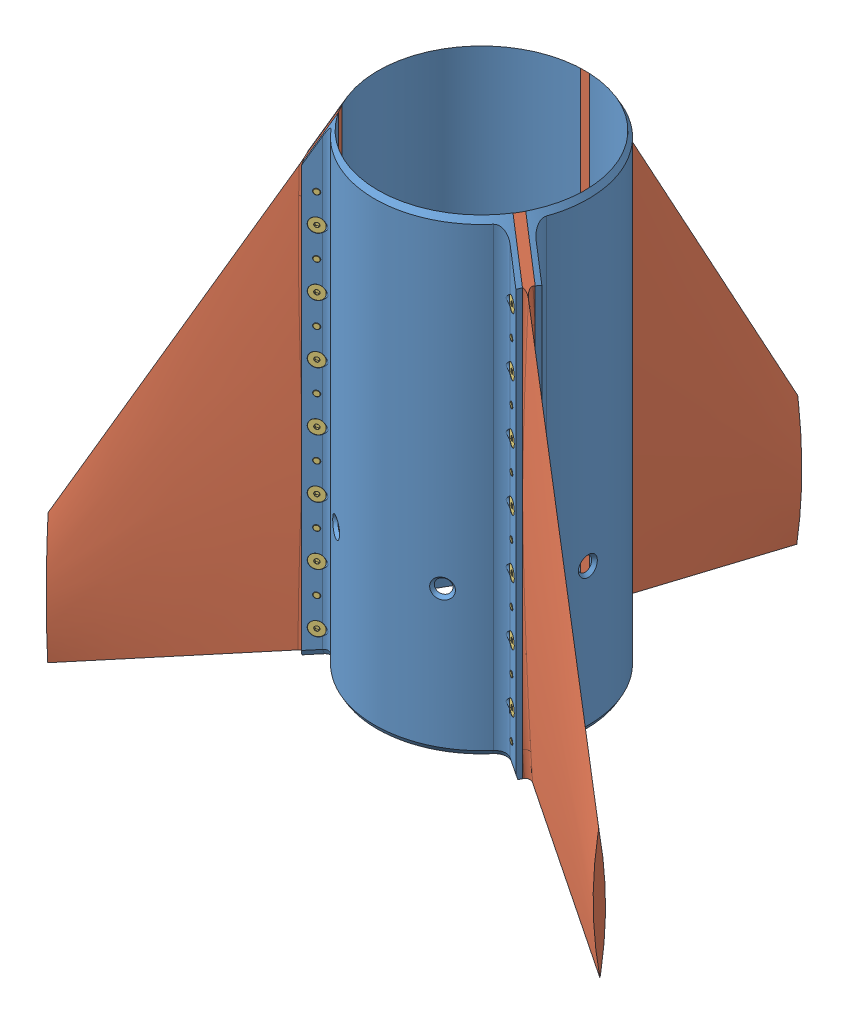
SolidWorks assembly Fin Can 3 Fin Asm 25-20, configuration Default. Lengths in mm.
Overall size (544.77 508.03 473.71).
48 component instances, 3 part files, 14 mates.
Components (placement in the parent):
- Binder Fin Can Section 3 25-20-1: Binder Fin Can Section 3 25-20 [Default] at origin size (110.04 463.46 186.39)
- BiconvexFin 3 Fin Fillet 25-20-4: BiconvexFin 3 Fin Fillet 25-20 [Default] at (85.524 466.7433 54.8623) x (0 -1 0) z (0.866025 0 0.5) size (507.85 12.04 209.48)
- BiconvexFin 3 Fin Fillet 25-20-5: BiconvexFin 3 Fin Fillet 25-20 [Default] at (4.7501 466.7433 -101.4971) x (0 -1 0) z (0 0 -1) size (507.85 12.04 209.48)
- BiconvexFin 3 Fin Fillet 25-20-6: BiconvexFin 3 Fin Fillet 25-20 [Default] at (-90.2741 466.7433 46.6348) x (0 -1 0) z (-0.866025 0 0.5) size (507.85 12.04 209.48)
- Binder Fin Can Section 3 25-20-2: Binder Fin Can Section 3 25-20 [Default] at (-0.0006 0.0001 0) x (-0.5 0 -0.866025) z (0.866025 0 -0.5) size (110.04 463.46 186.39)
- Binder Fin Can Section 3 25-20-3: Binder Fin Can Section 3 25-20 [Default] at (0 -0.0001 0) x (-0.5 0 0.866025) z (-0.866025 0 -0.5) size (110.04 463.46 186.39)
- 91253A307_Black-Oxide Alloy Steel Hex Drive Flat Head Screw-1: 91253A307_Black-Oxide Alloy Steel Hex Drive Flat Head Screw [91253A307] at (0.3215 28.575 -115.7846) x (0 -0.777599 0.628761) z (-1 0 0) size (13.49 13.49 19.62)
- 91253A307_Black-Oxide Alloy Steel Hex Drive Flat Head Screw-2: 91253A307_Black-Oxide Alloy Steel Hex Drive Flat Head Screw [91253A307] at (0.3215 85.725 -115.7846) x (0 -0.777599 0.628761) z (-1 0 0) size (13.49 13.49 19.62)
- 91253A307_Black-Oxide Alloy Steel Hex Drive Flat Head Screw-3: 91253A307_Black-Oxide Alloy Steel Hex Drive Flat Head Screw [91253A307] at (0.3215 142.875 -115.7846) x (0 -0.777599 0.628761) z (-1 0 0) size (13.49 13.49 19.62)
- 91253A307_Black-Oxide Alloy Steel Hex Drive Flat Head Screw-4: 91253A307_Black-Oxide Alloy Steel Hex Drive Flat Head Screw [91253A307] at (0.3215 200.025 -115.7846) x (0 -0.777599 0.628761) z (-1 0 0) size (13.49 13.49 19.62)
- 91253A307_Black-Oxide Alloy Steel Hex Drive Flat Head Screw-28: 91253A307_Black-Oxide Alloy Steel Hex Drive Flat Head Screw [91253A307] at (-0.3221 57.15 -115.7846) x (0 0.917872 0.396876) z (1 0 0) size (13.49 13.49 19.62)
- 91253A307_Black-Oxide Alloy Steel Hex Drive Flat Head Screw-29: 91253A307_Black-Oxide Alloy Steel Hex Drive Flat Head Screw [91253A307] at (-0.3221 114.3 -115.7846) x (0 0.917872 0.396876) z (1 0 0) size (13.49 13.49 19.62)
- 91253A307_Black-Oxide Alloy Steel Hex Drive Flat Head Screw-30: 91253A307_Black-Oxide Alloy Steel Hex Drive Flat Head Screw [91253A307] at (-0.3221 171.45 -115.7846) x (0 0.917872 0.396876) z (1 0 0) size (13.49 13.49 19.62)
- 91253A307_Black-Oxide Alloy Steel Hex Drive Flat Head Screw-31: 91253A307_Black-Oxide Alloy Steel Hex Drive Flat Head Screw [91253A307] at (-0.3221 228.6 -115.7846) x (0 0.917872 0.396876) z (1 0 0) size (13.49 13.49 19.62)
- 91253A307_Black-Oxide Alloy Steel Hex Drive Flat Head Screw-35: 91253A307_Black-Oxide Alloy Steel Hex Drive Flat Head Screw [91253A307] at (100.1114 28.5749 58.1712) x (-0.866025 0 -0.5) z (0.5 0 -0.866025) size (13.49 13.49 19.62)
- 91253A307_Black-Oxide Alloy Steel Hex Drive Flat Head Screw-36: 91253A307_Black-Oxide Alloy Steel Hex Drive Flat Head Screw [91253A307] at (100.1114 85.7249 58.1712) x (-0.866025 0 -0.5) z (0.5 0 -0.866025) size (13.49 13.49 19.62)
- 91253A307_Black-Oxide Alloy Steel Hex Drive Flat Head Screw-37: 91253A307_Black-Oxide Alloy Steel Hex Drive Flat Head Screw [91253A307] at (100.1114 142.8749 58.1712) x (-0.866025 0 -0.5) z (0.5 0 -0.866025) size (13.49 13.49 19.62)
- 91253A307_Black-Oxide Alloy Steel Hex Drive Flat Head Screw-38: 91253A307_Black-Oxide Alloy Steel Hex Drive Flat Head Screw [91253A307] at (100.1114 200.0249 58.1712) x (-0.866025 0 -0.5) z (0.5 0 -0.866025) size (13.49 13.49 19.62)
- 91253A307_Black-Oxide Alloy Steel Hex Drive Flat Head Screw-42: 91253A307_Black-Oxide Alloy Steel Hex Drive Flat Head Screw [91253A307] at (100.4334 57.1499 57.6134) x (0.414746 0.877865 0.239454) z (-0.5 0 0.866025) size (13.49 13.49 19.62)
- 91253A307_Black-Oxide Alloy Steel Hex Drive Flat Head Screw-43: 91253A307_Black-Oxide Alloy Steel Hex Drive Flat Head Screw [91253A307] at (100.4334 114.2999 57.6134) x (0.414746 0.877865 0.239454) z (-0.5 0 0.866025) size (13.49 13.49 19.62)
- 91253A307_Black-Oxide Alloy Steel Hex Drive Flat Head Screw-44: 91253A307_Black-Oxide Alloy Steel Hex Drive Flat Head Screw [91253A307] at (100.4334 171.4499 57.6134) x (0.414746 0.877865 0.239454) z (-0.5 0 0.866025) size (13.49 13.49 19.62)
- 91253A307_Black-Oxide Alloy Steel Hex Drive Flat Head Screw-45: 91253A307_Black-Oxide Alloy Steel Hex Drive Flat Head Screw [91253A307] at (100.4334 228.5999 57.6134) x (0.414746 0.877865 0.239454) z (-0.5 0 0.866025) size (13.49 13.49 19.62)
- 91253A307_Black-Oxide Alloy Steel Hex Drive Flat Head Screw-49: 91253A307_Black-Oxide Alloy Steel Hex Drive Flat Head Screw [91253A307] at (-100.4339 28.5751 57.6136) x (-0.801823 -0.377852 0.462933) z (0.5 0 0.866025) size (13.49 13.49 19.62)
- 91253A307_Black-Oxide Alloy Steel Hex Drive Flat Head Screw-50: 91253A307_Black-Oxide Alloy Steel Hex Drive Flat Head Screw [91253A307] at (-100.4339 85.7251 57.6136) x (-0.801823 -0.377852 0.462933) z (0.5 0 0.866025) size (13.49 13.49 19.62)
- 91253A307_Black-Oxide Alloy Steel Hex Drive Flat Head Screw-51: 91253A307_Black-Oxide Alloy Steel Hex Drive Flat Head Screw [91253A307] at (-100.4339 142.8751 57.6136) x (-0.801823 -0.377852 0.462933) z (0.5 0 0.866025) size (13.49 13.49 19.62)
- 91253A307_Black-Oxide Alloy Steel Hex Drive Flat Head Screw-52: 91253A307_Black-Oxide Alloy Steel Hex Drive Flat Head Screw [91253A307] at (-100.4339 200.0251 57.6136) x (-0.801823 -0.377852 0.462933) z (0.5 0 0.866025) size (13.49 13.49 19.62)
- 91253A307_Black-Oxide Alloy Steel Hex Drive Flat Head Screw-56: 91253A307_Black-Oxide Alloy Steel Hex Drive Flat Head Screw [91253A307] at (-100.112 57.1501 58.1712) x (-0.624176 0.693209 0.360368) z (-0.5 0 -0.866025) size (13.49 13.49 19.62)
- 91253A307_Black-Oxide Alloy Steel Hex Drive Flat Head Screw-57: 91253A307_Black-Oxide Alloy Steel Hex Drive Flat Head Screw [91253A307] at (-100.112 114.3001 58.1712) x (-0.624176 0.693209 0.360368) z (-0.5 0 -0.866025) size (13.49 13.49 19.62)
- 91253A307_Black-Oxide Alloy Steel Hex Drive Flat Head Screw-58: 91253A307_Black-Oxide Alloy Steel Hex Drive Flat Head Screw [91253A307] at (-100.112 171.4501 58.1712) x (-0.624176 0.693209 0.360368) z (-0.5 0 -0.866025) size (13.49 13.49 19.62)
- 91253A307_Black-Oxide Alloy Steel Hex Drive Flat Head Screw-59: 91253A307_Black-Oxide Alloy Steel Hex Drive Flat Head Screw [91253A307] at (-100.112 228.6001 58.1712) x (-0.624176 0.693209 0.360368) z (-0.5 0 -0.866025) size (13.49 13.49 19.62)
- 91253A307_Black-Oxide Alloy Steel Hex Drive Flat Head Screw-25: 91253A307_Black-Oxide Alloy Steel Hex Drive Flat Head Screw [91253A307] at (0.3215 257.175 -115.7846) x (0 -0.777599 0.628761) z (-1 0 0) size (13.49 13.49 19.62)
- 91253A307_Black-Oxide Alloy Steel Hex Drive Flat Head Screw-26: 91253A307_Black-Oxide Alloy Steel Hex Drive Flat Head Screw [91253A307] at (0.3215 314.325 -115.7846) x (0 -0.777599 0.628761) z (-1 0 0) size (13.49 13.49 19.62)
- 91253A307_Black-Oxide Alloy Steel Hex Drive Flat Head Screw-27: 91253A307_Black-Oxide Alloy Steel Hex Drive Flat Head Screw [91253A307] at (0.3215 371.475 -115.7846) x (0 -0.777599 0.628761) z (-1 0 0) size (13.49 13.49 19.62)
- 91253A307_Black-Oxide Alloy Steel Hex Drive Flat Head Screw-32: 91253A307_Black-Oxide Alloy Steel Hex Drive Flat Head Screw [91253A307] at (-0.3221 285.75 -115.7846) x (0 0.917872 0.396876) z (1 0 0) size (13.49 13.49 19.62)
- 91253A307_Black-Oxide Alloy Steel Hex Drive Flat Head Screw-33: 91253A307_Black-Oxide Alloy Steel Hex Drive Flat Head Screw [91253A307] at (-0.3221 342.9 -115.7846) x (0 0.917872 0.396876) z (1 0 0) size (13.49 13.49 19.62)
- 91253A307_Black-Oxide Alloy Steel Hex Drive Flat Head Screw-34: 91253A307_Black-Oxide Alloy Steel Hex Drive Flat Head Screw [91253A307] at (-0.3221 400.05 -115.7846) x (0 0.917872 0.396876) z (1 0 0) size (13.49 13.49 19.62)
- 91253A307_Black-Oxide Alloy Steel Hex Drive Flat Head Screw-39: 91253A307_Black-Oxide Alloy Steel Hex Drive Flat Head Screw [91253A307] at (100.1114 257.1749 58.1712) x (-0.866025 0 -0.5) z (0.5 0 -0.866025) size (13.49 13.49 19.62)
- 91253A307_Black-Oxide Alloy Steel Hex Drive Flat Head Screw-40: 91253A307_Black-Oxide Alloy Steel Hex Drive Flat Head Screw [91253A307] at (100.1114 314.3249 58.1712) x (-0.866025 0 -0.5) z (0.5 0 -0.866025) size (13.49 13.49 19.62)
- 91253A307_Black-Oxide Alloy Steel Hex Drive Flat Head Screw-41: 91253A307_Black-Oxide Alloy Steel Hex Drive Flat Head Screw [91253A307] at (100.1114 371.4749 58.1712) x (-0.866025 0 -0.5) z (0.5 0 -0.866025) size (13.49 13.49 19.62)
- 91253A307_Black-Oxide Alloy Steel Hex Drive Flat Head Screw-46: 91253A307_Black-Oxide Alloy Steel Hex Drive Flat Head Screw [91253A307] at (100.4334 285.7499 57.6134) x (0.414746 0.877865 0.239454) z (-0.5 0 0.866025) size (13.49 13.49 19.62)
- 91253A307_Black-Oxide Alloy Steel Hex Drive Flat Head Screw-47: 91253A307_Black-Oxide Alloy Steel Hex Drive Flat Head Screw [91253A307] at (100.4334 342.8999 57.6134) x (0.414746 0.877865 0.239454) z (-0.5 0 0.866025) size (13.49 13.49 19.62)
- 91253A307_Black-Oxide Alloy Steel Hex Drive Flat Head Screw-48: 91253A307_Black-Oxide Alloy Steel Hex Drive Flat Head Screw [91253A307] at (100.4334 400.0499 57.6134) x (0.414746 0.877865 0.239454) z (-0.5 0 0.866025) size (13.49 13.49 19.62)
- 91253A307_Black-Oxide Alloy Steel Hex Drive Flat Head Screw-53: 91253A307_Black-Oxide Alloy Steel Hex Drive Flat Head Screw [91253A307] at (-100.4339 257.1751 57.6136) x (-0.801823 -0.377852 0.462933) z (0.5 0 0.866025) size (13.49 13.49 19.62)
- 91253A307_Black-Oxide Alloy Steel Hex Drive Flat Head Screw-54: 91253A307_Black-Oxide Alloy Steel Hex Drive Flat Head Screw [91253A307] at (-100.4339 314.3251 57.6136) x (-0.801823 -0.377852 0.462933) z (0.5 0 0.866025) size (13.49 13.49 19.62)
- 91253A307_Black-Oxide Alloy Steel Hex Drive Flat Head Screw-55: 91253A307_Black-Oxide Alloy Steel Hex Drive Flat Head Screw [91253A307] at (-100.4339 371.4751 57.6136) x (-0.801823 -0.377852 0.462933) z (0.5 0 0.866025) size (13.49 13.49 19.62)
- 91253A307_Black-Oxide Alloy Steel Hex Drive Flat Head Screw-60: 91253A307_Black-Oxide Alloy Steel Hex Drive Flat Head Screw [91253A307] at (-100.112 285.7501 58.1712) x (-0.624176 0.693209 0.360368) z (-0.5 0 -0.866025) size (13.49 13.49 19.62)
- 91253A307_Black-Oxide Alloy Steel Hex Drive Flat Head Screw-61: 91253A307_Black-Oxide Alloy Steel Hex Drive Flat Head Screw [91253A307] at (-100.112 342.9001 58.1712) x (-0.624176 0.693209 0.360368) z (-0.5 0 -0.866025) size (13.49 13.49 19.62)
- 91253A307_Black-Oxide Alloy Steel Hex Drive Flat Head Screw-62: 91253A307_Black-Oxide Alloy Steel Hex Drive Flat Head Screw [91253A307] at (-100.112 400.0501 58.1712) x (-0.624176 0.693209 0.360368) z (-0.5 0 -0.866025) size (13.49 13.49 19.62)
Mates (geometry in assembly coordinates):
- Coincident1: coincident anti-aligned: plane of Binder Fin Can Section 3 25-20-1 through (90.185 508 46.7891) normal (-0.5 0 0.866025); plane of BiconvexFin 3 Fin Fillet-4 through (561.5246 496.7626 318.9171) normal (0.5 0 -0.866025)
- Coincident2: coincident aligned: plane of Binder Fin Can Section 3 25-20-1 through (114.5633 508 55.3646) normal (0.866025 0 0.5); plane of BiconvexFin 3 Fin Fillet-4 through (107.4867 466.7433 67.6218) normal (0.866025 0 0.5)
- Concentric1: concentric aligned: cylinder of BiconvexFin 3 Fin Fillet 25-20-4 through (97.9864 28.5749 61.8518) axis (-0.5 0 0.866025) radius 3.2639; circle of Binder Fin Can Section 3 25-20-1
- Concentric2: concentric: cylinder of Binder Fin Can Section 3 - countersink 1-2 through (-4.572 28.5749 -114.1971) axis (1 0 0) radius 2.4892; circle of 92210A197_18-8 8-32 Stainless Steel Hex Drive Flat Head Screw-1
- Coincident3: coincident aligned: cone of Binder Fin Can Section 3 25-20-2 through (-1.364 28.575 -115.7846) axis (1 0 0); cone of 92210A197_18-8 8-32 Stainless Steel Hex Drive Flat Head Screw-1 through (-5.5498 34.9247 -114.2076) axis (1 0 0)
- Concentric3: concentric anti-aligned: circle of 91253A307_Black-Oxide Alloy Steel Hex Drive Flat Head Screw-1; cylinder of Binder Fin Can Section 3 25-20-1 through (4.572 28.575 -115.7846) axis (-1 0 0) radius 2.4892
- Coincident4: coincident aligned: cone of Binder Fin Can Section 3 25-20-2 through (-1.364 28.575 -115.7846) axis (1 0 0); cone of 91253A307_Black-Oxide Alloy Steel Hex Drive Flat Head Screw-1 through (-5.1141 28.575 -115.7846) axis (1 0 0)
- Coincident5: coincident aligned: cone of Binder Fin Can Section 3 25-20-1 through (1.3634 57.15 -115.7846) axis (-1 0 0); cone of 91253A307_Black-Oxide Alloy Steel Hex Drive Flat Head Screw-28 through (5.1135 57.15 -115.7846) axis (-1 0 0)
- Concentric5: concentric anti-aligned: cylinder of Binder Fin Can Section 3 25-20-3 through (97.9864 28.5749 61.8518) axis (0.5 0 -0.866025) radius 2.4892; circle of 91253A307_Black-Oxide Alloy Steel Hex Drive Flat Head Screw-35
- Coincident6: coincident aligned: cone of Binder Fin Can Section 3 25-20-1 through (100.9541 28.5749 56.7115) axis (-0.5 0 0.866025); cone of 91253A307_Black-Oxide Alloy Steel Hex Drive Flat Head Screw-35 through (102.8292 28.5749 53.4638) axis (-0.5 0 0.866025)
- Coincident7: coincident aligned: cone of Binder Fin Can Section 3 25-20-3 through (99.5907 57.1499 59.073) axis (0.5 0 -0.866025); cone of 91253A307_Black-Oxide Alloy Steel Hex Drive Flat Head Screw-42 through (97.7156 57.1499 62.3207) axis (0.5 0 -0.866025)
- Concentric7: concentric anti-aligned: circle of 91253A307_Black-Oxide Alloy Steel Hex Drive Flat Head Screw-49; cylinder of Binder Fin Can Section 3 25-20-2 through (-102.559 28.5751 53.9328) axis (0.5 0 0.866025) radius 2.4892
- Coincident8: coincident aligned: cone of Binder Fin Can Section 3 25-20-3 through (-99.5907 28.5747 59.073) axis (-0.5 0 -0.866025); cone of 91253A307_Black-Oxide Alloy Steel Hex Drive Flat Head Screw-49 through (-97.7161 28.5751 62.321) axis (-0.5 0 -0.866025)
- Coincident12: coincident aligned: cone of Binder Fin Can Section 3 25-20-2 through (-100.9547 57.1501 56.7115) axis (0.5 0 0.866025); cone of 91253A307_Black-Oxide Alloy Steel Hex Drive Flat Head Screw-56 through (-102.8298 57.1501 53.4638) axis (0.5 0 0.866025)
